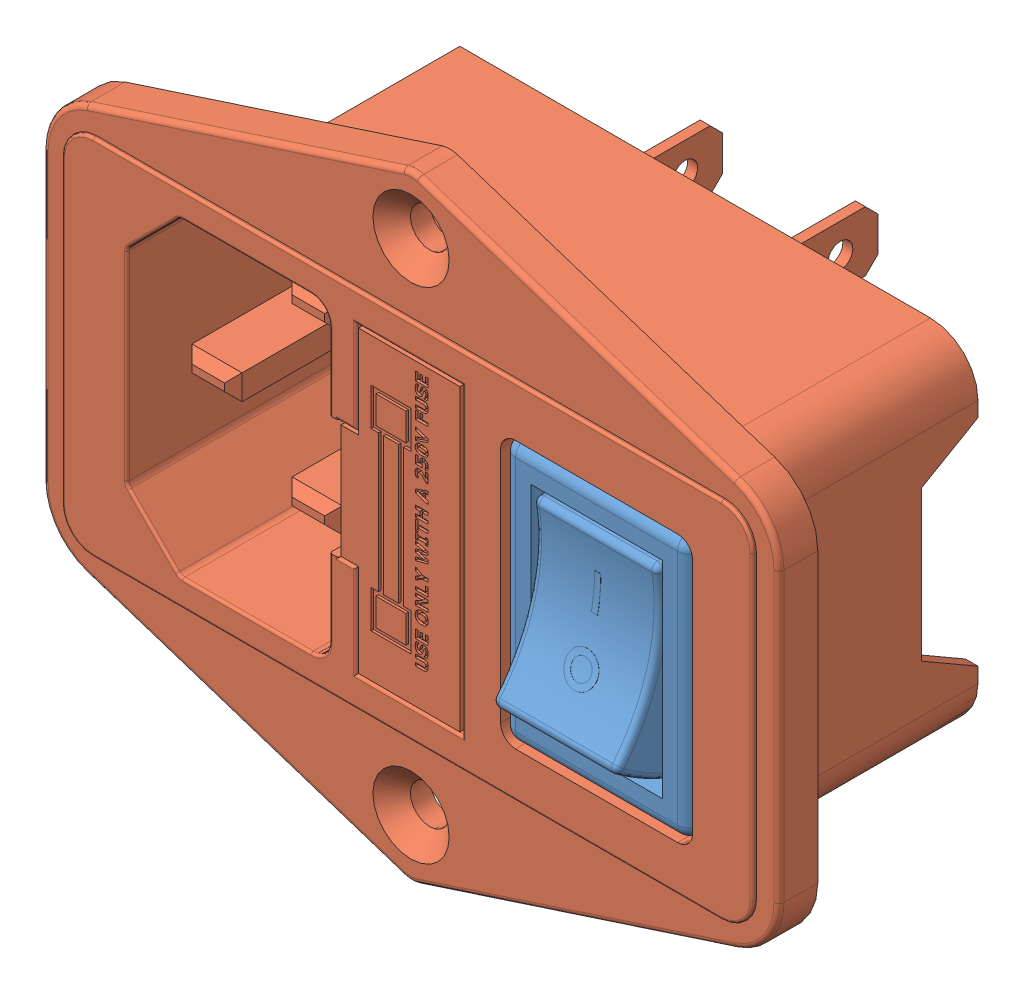
SolidWorks assembly enchufe, configuration Predeterminado. Lengths in mm.
Overall size (58.8 49.2 35.22).
3 component instances, 2 part files, 0 mates.
Components (placement in the parent):
- enchufe.stp-1: enchufe.stp [Predeterminado] at origin size (58.8 49.2 35.22)
  - ARCOLECTRIC_H8600VB.stp-1: ARCOLECTRIC_H8600VB.stp [Predeterminado] at (38.0572 26.309 49.8243) x (-1 0 0) z (0 1 0) size (14.95 25.77 20.95)
  - Разъём.stp-1: Разъём.stp [Predeterminado] at (-4.6678 12.034 48.4243) size (58.8 49.2 31.9)
